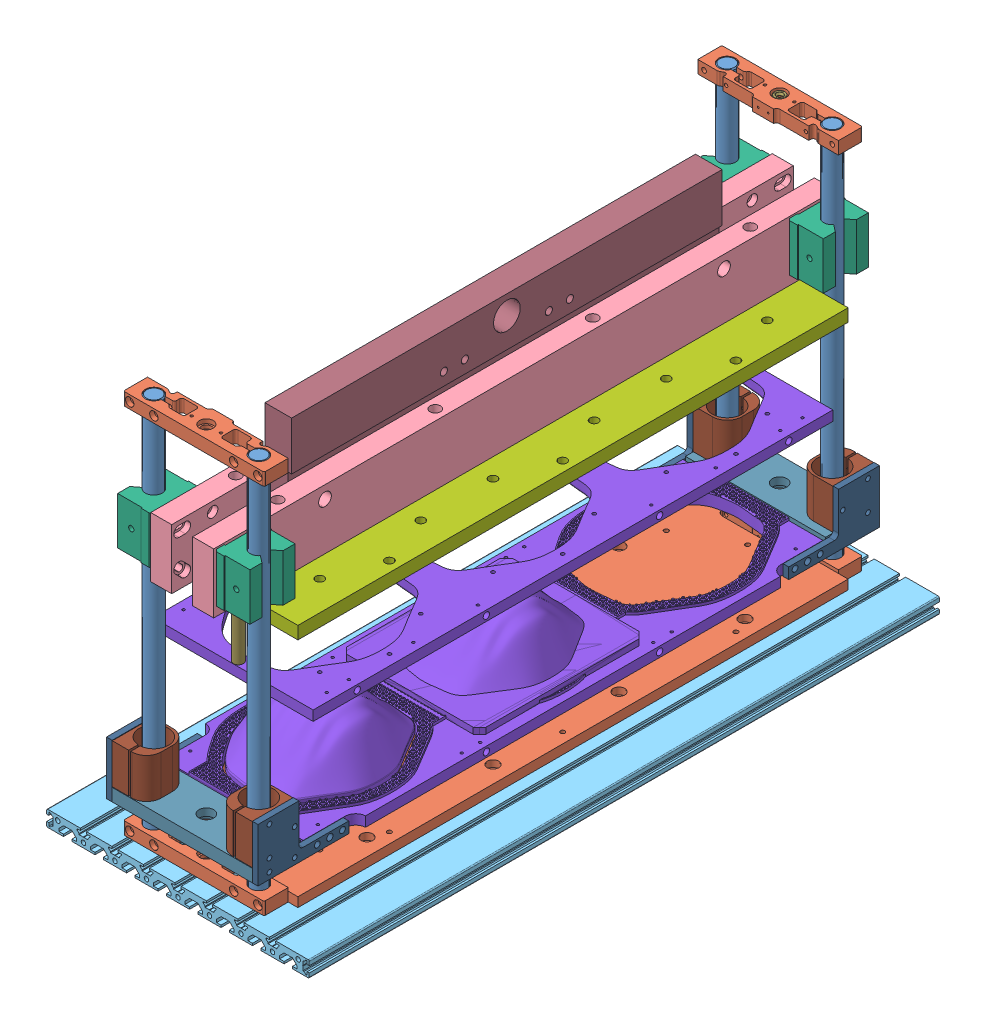
SolidWorks assembly MaskPress, configuration Default. Lengths in mm.
Overall size (250 384.22 600.9).
40 component instances, 14 part files, 64 mates.
Components (placement in the parent):
- 7121045-Z-ZShaft-2: 7121045-Z-ZShaft [Default] at (50 198 -273) x (0.850802 0 -0.525486) z (0.525486 0 0.850802) size (16 366 16)
- 7121045-Z-ZShaft-3: 7121045-Z-ZShaft [Default] at (-50 198 -273) x (0.889687 0 -0.456571) z (0.456571 0 0.889687) size (16 366 16)
- 2MaskBottomPlate2-1: 2MaskBottomPlate2 [Default] at (0 21 -273) x (1 0 0) z (0 0 -1) size (134 12 27.75)
- 2MaskBottomPlate2-2: 2MaskBottomPlate2 [Default] at (0 375 -273) x (1 0 0) z (0 0 -1) size (134 12 27.75)
- 7121502-6mmBearing-2: 7121502-6mmBearing [Default] at (0 378.5 -273) x (0.973392 0 -0.229147) z (0 -1 0) size (10 10 3)
- 7121045-Z-ZShaft-4: 7121045-Z-ZShaft [Default] at (50 198 273) x (0.850802 0 0.525486) z (-0.525486 0 0.850802) size (16 366 16)
- 7121045-Z-ZShaft-5: 7121045-Z-ZShaft [Default] at (-50 198 273) x (0.889687 0 0.456571) z (-0.456571 0 0.889687) size (16 366 16)
- 2MaskBottomPlate2-3: 2MaskBottomPlate2 [Default] at (0 21 273) x (-1 0 0) z (0 0 1) size (134 12 27.75)
- 2MaskBottomPlate2-4: 2MaskBottomPlate2 [Default] at (0 375 273) x (-1 0 0) z (0 0 1) size (134 12 27.75)
- Crosspiece-1: Crosspiece [Default] at (20 232.7807 0) x (1 0 0) z (0 0 -1) size (20 57 592)
- HFSQN4-15250-600-1: HFSQN4-15250-600 [Default] at (0 15 -300) x (-1 0 0) z (0 0 1) size (250 15 600)
- BearingBlock-RLG16-1: BearingBlock-RLG16 [BearingBlock] at (50 280.7807 -273) x (0 0 -1) z (0 1 0) size (50.4 50.24 45)
- BearingBlock-RLG16-2: BearingBlock-RLG16 [BearingBlock] at (50 280.7807 273) x (0 0 -1) z (0 1 0) size (50.4 50.24 45)
- Crosspiece-2: Crosspiece [Default] at (-20 232.7807 0) x (-1 0 0) z (0 0 1) size (20 57 592)
- BearingBlock-RLG16-3: BearingBlock-RLG16 [BearingBlock] at (-50 280.7807 -273) x (0 0 -1) z (0 -1 0) size (50.4 50.24 45)
- BearingBlock-RLG16-4: BearingBlock-RLG16 [BearingBlock] at (-50 280.7807 273) x (0 0 -1) z (0 -1 0) size (50.4 50.24 45)
- 2MaskBottomPlate2-5: 2MaskBottomPlate2 [Baseplate] at (0 21 273) size (161.21 9 568.5)
- TopPlate-1: TopPlate [Default] at (0 241.7807 0) x (0 0 -1) z (1 0 0) size (524 75.7 152.4)
- N95_Mask_Mold-1: N95_Mask_Mold [Default] at (-3.8223 61.75 0) x (0 0 -1) z (0 1 0) size (147.26 125.94 76.23)
- ShoulderScrew-ISO7379-1: ShoulderScrew-ISO7379 [M5-6Dx20L] at (28.2071 44.02 -71.5893) x (0 -1 0) z (0 0 1) size (31.12 11.61 10)
- N95_Mask_Mold-2: N95_Mask_Mold [BottomDie] at (-3.8223 49.27 0) x (0 0 1) z (0 -1 0) size (495.2 152.4 81.89)
- SteelBracket-1: SteelBracket [Default] at (66.75 47.75 296) x (0 0 -1) z (1 0 0) size (86.5 50.8 5.4)
- ClampingBearingBlock-1: ClampingBearingBlock [Default] at (50 79.3 273) x (0 0 -1) z (0 1 0) size (39 32.75 38)
- ClampingBearingBlock-2: ClampingBearingBlock [Default] at (50 79.3 -273) x (0 0 1) z (0 -1 0) size (39 32.75 38)
- SteelBracket-2: SteelBracket [Default] at (72.15 47.75 -296) x (0 0 1) z (-1 0 0) size (86.5 50.8 5.4)
- SteelBracket-3: SteelBracket [Default] at (-66.75 47.75 -296) x (0 0 1) z (-1 0 0) size (86.5 50.8 5.4)
- SteelBracket-4: SteelBracket [Default] at (-72.15 47.75 296) x (0 0 -1) z (1 0 0) size (86.5 50.8 5.4)
- ClampingBearingBlock-3: ClampingBearingBlock [Default] at (-50 79.3 273) x (0 0 -1) z (0 -1 0) size (39 32.75 38)
- ClampingBearingBlock-4: ClampingBearingBlock [Default] at (-50 79.3 -273) x (0 0 1) z (0 1 0) size (39 32.75 38)
- N95_Mask_Mold-3: N95_Mask_Mold [TopDie] at (-3.8223 170.5307 0) x (0 0 -1) z (0 1 0) size (531 152.4 13.77)
- Standoff-1: Standoff [Default] at (0 235.7807 -82.5) x (0.390754 0 0.920495) z (0 -1 0) size (9.53 9.53 65)
- Standoff-2: Standoff [Default] at (0 235.7807 82.5) x (0.79002 0 -0.61308) z (0 -1 0) size (9.53 9.53 65)
- Standoff-3: Standoff [Default] at (0 235.7807 242.5) x (0.79002 0 -0.61308) z (0 -1 0) size (9.53 9.53 65)
- Standoff-4: Standoff [Default] at (0 235.7807 -242.5) x (0.390754 0 0.920495) z (0 -1 0) size (9.53 9.53 65)
- Standoff-5: Standoff [17] at (0 23 30) x (1 0 0) z (0 1 0) size (9.53 9.53 17)
- Standoff-6: Standoff [17] at (0 23 -30) x (1 0 0) z (0 1 0) size (9.53 9.53 17)
- PressConnector-1: PressConnector [Default] at (0.5 320.6807 0) x (0 0 -1) z (1 0 0) size (410 76.2 25.4)
- SpringPlate-1: SpringPlate [Default] at (0 47.75 -273) x (1 0 0) z (0 1 0) size (133.5 46 12)
- SpringPlate-2: SpringPlate [Default] at (0 47.75 273) x (-1 0 0) z (0 1 0) size (133.5 46 12)
- N95_Mask_Mold-4: N95_Mask_Mold [Default] at (-3.8223 61.75 165) x (0 0 -1) z (0 1 0) size (147.26 125.94 76.23)
Mates (geometry in assembly coordinates):
- Coincident5: coincident: plane of ? through (0 0 0) normal (1 0 0); plane of assembly through (0 0 0) normal (1 0 0)
- Concentric1: concentric: cylinder of ? through (53 -169 -249) axis (0 1 0) radius 8; cylinder of ? through (53 405.5 -249) axis (0 -1 0) radius 8
- Concentric2: concentric: cylinder of ? through (53 30.5 -279) axis (0 0 -1) radius 2.9; cylinder of ? through (53 30.5 -257) axis (0 0 -1) radius 2.1
- Concentric182: concentric aligned: cylinder of 2MaskBottomPlate2-1 through (-50 15 -273) axis (0 1 0) radius 8; cylinder of 7121045-Z-ZShaft-3 through (-50 381 -273) axis (0 1 0) radius 8
- Concentric240: concentric aligned: cylinder of 7121045-Z-ZShaft-3 through (-50 381 -273) axis (0 1 0) radius 8; cylinder of 2MaskBottomPlate2-2 through (-50 369 -273) axis (0 1 0) radius 8
- Concentric242: concentric aligned: cylinder of 7121045-Z-ZShaft-2 through (50 381 -273) axis (0 1 0) radius 8; cylinder of 2MaskBottomPlate2-2 through (50 369 -273) axis (0 1 0) radius 8
- Coincident203: coincident aligned: plane of 7121045-Z-ZShaft-2 through (55.9556 381 -276.6784) normal (0 1 0); plane of 2MaskBottomPlate2-2 through (65.5 381 -283.5) normal (0 1 0)
- Coincident204: coincident aligned: plane of 7121045-Z-ZShaft-3 through (-43.7722 381 -276.196) normal (0 1 0); plane of 2MaskBottomPlate2-2 through (65.5 381 -283.5) normal (0 1 0)
- Coincident206: coincident anti-aligned: plane of 2MaskBottomPlate2-2 through (6.5 377 -273) normal (0 1 0); plane of 7121502-6mmBearing-2 through (1.1114 377 -268.2791) normal (0 -1 0)
- Parallel2: parallel anti-aligned: plane of 2MaskBottomPlate2-2 through (65.5 369 -285) normal (0 0 -1)
- Coincident244: coincident aligned: plane of 7121045-Z-ZShaft-2 through (55.9556 15 -276.6784) normal (0 -1 0); plane of 2MaskBottomPlate2-1 through (65.5 15 -283.5) normal (0 -1 0)
- Concentric281: concentric anti-aligned: cylinder of BearingBlock-RLG16-1 through (50 303.2807 -273) axis (0 -1 0) radius 8; cylinder of 7121045-Z-ZShaft-2 through (50 381 -273) axis (0 1 0) radius 8
- Parallel4: parallel anti-aligned: plane of BearingBlock-RLG16-1 through (30 303.2807 -252.5) normal (-1 0 0)
- Concentric282: concentric anti-aligned: cylinder of BearingBlock-RLG16-2 through (50 303.2807 273) axis (0 -1 0) radius 8; cylinder of 7121045-Z-ZShaft-4 through (50 381 273) axis (0 1 0) radius 8
- Coincident254: coincident aligned: plane of BearingBlock-RLG16-1 through (50 303.2807 -273) normal (0 1 0); plane of BearingBlock-RLG16-2 through (50 303.2807 273) normal (0 1 0)
- Coincident257: coincident anti-aligned: plane of 2MaskBottomPlate2-3 through (-65.5 15 283.5) normal (0 -1 0); plane of HFSQN4-15250-600-1 through (27 15 300) normal (0 1 0)
- Coincident258: coincident aligned: unknown of HFSQN4-15250-600-1
- Coincident259: coincident anti-aligned: plane of HFSQN4-15250-600-1 through (0 15 -300) normal (-1 0 0)
- Coincident260: coincident anti-aligned: plane of HFSQN4-15250-600-1 through (-124 0 300) normal (0 -1 0)
- Concentric285: concentric aligned: cylinder of Crosspiece-1 through (37.2801 295.7807 257) axis (-1 0 0) radius 2.9; cylinder of BearingBlock-RLG16-2 through (30 295.7807 257) axis (-1 0 0) radius 2.1
- Concentric287: concentric aligned: cylinder of Crosspiece-1 through (37.2801 295.7807 -257) axis (-1 0 0) radius 2.9; cylinder of BearingBlock-RLG16-1 through (30 295.7807 -257) axis (-1 0 0) radius 2.1
- Coincident261: coincident anti-aligned: plane of Crosspiece-1 through (30 247.7807 -296) normal (1 0 0); plane of BearingBlock-RLG16-2 through (30 303.2807 252.5) normal (-1 0 0)
- Concentric288: concentric aligned: cylinder of 7121045-Z-ZShaft-4 through (50 381 273) axis (0 1 0) radius 8; cylinder of 2MaskBottomPlate2-3 through (50 15 273) axis (0 1 0) radius 8
- Coincident262: coincident anti-aligned: plane of HFSQN4-15250-600-1 through (-3 15 300) normal (0 1 0); plane of 7121004-H4A-ZShaftClamp-5 through (-35.25 15 -260) normal (0 -1 0)
- Coincident263: coincident anti-aligned: plane of HFSQN4-15250-600-1 through (0 15 -300) normal (-1 0 0); plane of 7121004-H4A-ZShaftClamp-5 through (0 21 273) normal (1 0 0)
- Coincident264: coincident anti-aligned: plane of 2MaskBottomPlate2-1 through (0 15 -262) normal (0 0 1); plane of 7121004-H4A-ZShaftClamp-5 through (-76.2 24 -262) normal (0 0 -1)
- Concentric289: concentric aligned: cylinder of Crosspiece-1 through (20 304.7807 225) axis (0 1 0) radius 2.75; cylinder of TopPlate-1 through (20 247.7807 225) axis (0 1 0) radius 2.1
- Coincident265: coincident anti-aligned: plane of Crosspiece-1 through (10 247.7807 -296) normal (0 -1 0); plane of TopPlate-1 through (0 247.7807 0) normal (0 1 0)
- Concentric290: concentric aligned: cylinder of Crosspiece-1 through (20 304.7807 -225) axis (0 1 0) radius 2.75; cylinder of TopPlate-1 through (20 247.7807 -225) axis (0 1 0) radius 2.1
- Coincident272: coincident anti-aligned: plane of assembly through (0 0 0) normal (0 0 1); plane of N95_Mask_Mold-1 through (-3.8223 61.75 0) normal (0 0 -1)
- Coincident275: coincident anti-aligned: plane of N95_Mask_Mold-1 through (0 61.75 0) normal (-1 0 0)
- Coincident276: coincident anti-aligned: plane of 2MaskBottomPlate2-5 through (-35.25 24 -260) normal (0 1 0); plane of ShoulderScrew-ISO7379-1 through (30.3416 24 -71.5893) normal (0 -1 0)
- Coincident277: coincident aligned: plane of N95_Mask_Mold-1 through (-3.8223 61.75 0) normal (-1 0 0); plane of N95_Mask_Mold-2 through (-3.8223 49.27 0) normal (-1 0 0)
- Coincident278: coincident anti-aligned: plane of N95_Mask_Mold-1 through (-3.8223 61.75 0) normal (0 0 -1); plane of N95_Mask_Mold-2 through (-3.8223 49.27 0) normal (0 0 1)
- Coincident279: coincident anti-aligned: plane of ShoulderScrew-ISO7379-1 through (32.9071 49.02 -71.5893) normal (0 1 0); plane of N95_Mask_Mold-2 through (-3.8223 49.02 165) normal (0 -1 0)
- Concentric295: concentric anti-aligned: cylinder of N95_Mask_Mold-2 through (66.75 53.75 215.5) axis (1 0 0) radius 2.1; cylinder of SteelBracket-1 through (72.15 53.75 215.5) axis (-1 0 0) radius 2.75
- Concentric297: concentric anti-aligned: cylinder of 7121045-Z-ZShaft-4 through (50 381 273) axis (0 1 0) radius 8; cylinder of ClampingBearingBlock-1 through (50 98.3 273) axis (0 -1 0) radius 14
- Parallel5: parallel aligned: plane of N95_Mask_Mold-2 through (66.75 61.03 247.5) normal (1 0 0); plane of ClampingBearingBlock-1 through (66.75 98.3 273) normal (1 0 0)
- Distance11: distance = 32 mm anti-aligned: plane of 2MaskBottomPlate2-3 through (-65.5 27 283.5) normal (0 1 0); plane of ClampingBearingBlock-1 through (50 60.3 273) normal (0 -1 0)
- Concentric298: concentric anti-aligned: cylinder of SteelBracket-1 through (72.15 79.3 261) axis (-1 0 0) radius 2.25; cylinder of ClampingBearingBlock-1 through (67 79.3 261) axis (1 0 0) radius 1.65
- Coincident288: coincident anti-aligned: plane of SteelBracket-1 through (66.75 47.75 296) normal (-1 0 0); plane of ClampingBearingBlock-1 through (66.75 98.3 273) normal (1 0 0)
- Coincident289: coincident aligned: plane of N95_Mask_Mold-2 through (-3.8223 49.27 0) normal (-1 0 0); plane of N95_Mask_Mold-3 through (-3.8223 170.5307 0) normal (-1 0 0)
- Coincident290: coincident anti-aligned: plane of N95_Mask_Mold-2 through (-3.8223 49.27 0) normal (0 0 1); plane of N95_Mask_Mold-3 through (-3.8223 170.5307 0) normal (0 0 -1)
- Concentric299: concentric anti-aligned: cylinder of N95_Mask_Mold-3 through (0 161.3207 -82.5) axis (0 -1 0) radius 1.65; cylinder of Standoff-1 through (0 170.7807 -82.5) axis (0 1 0) radius 4.7625
- Coincident291: coincident anti-aligned: plane of N95_Mask_Mold-3 through (-3.8223 170.7807 -165) normal (0 1 0); plane of Standoff-1 through (0 170.7807 -82.5) normal (0 -1 0)
- Coincident292: coincident anti-aligned: plane of TopPlate-1 through (0 235.7807 0) normal (0 -1 0); plane of Standoff-1 through (0 235.7807 -82.5) normal (0 1 0)
- Concentric300: concentric anti-aligned: cylinder of N95_Mask_Mold-3 through (0 161.3207 82.5) axis (0 -1 0) radius 1.65; cylinder of Standoff-2 through (0 170.7807 82.5) axis (0 1 0) radius 4.7625
- Coincident293: coincident anti-aligned: plane of TopPlate-1 through (0 235.7807 0) normal (0 -1 0); plane of Standoff-2 through (0 235.7807 82.5) normal (0 1 0)
- Concentric301: concentric anti-aligned: cylinder of N95_Mask_Mold-3 through (0 161.3207 242.5) axis (0 -1 0) radius 1.65; cylinder of Standoff-3 through (0 170.7807 242.5) axis (0 1 0) radius 4.7625
- Coincident294: coincident anti-aligned: plane of N95_Mask_Mold-3 through (-3.8223 170.7807 -165) normal (0 1 0); plane of Standoff-3 through (0 170.7807 242.5) normal (0 -1 0)
- Concentric302: concentric anti-aligned: cylinder of N95_Mask_Mold-3 through (0 161.3207 -242.5) axis (0 -1 0) radius 1.65; cylinder of Standoff-4 through (0 170.7807 -242.5) axis (0 1 0) radius 4.7625
- Coincident295: coincident anti-aligned: plane of N95_Mask_Mold-3 through (-3.8223 170.7807 -165) normal (0 1 0); plane of Standoff-4 through (0 170.7807 -242.5) normal (0 -1 0)
- Concentric303: concentric anti-aligned: cylinder of 2MaskBottomPlate2-5 through (0 23 -30) axis (0 1 0) radius 4.826; cylinder of Standoff-6 through (0 40 -30) axis (0 -1 0) radius 4.7625
- Concentric304: concentric anti-aligned: cylinder of 2MaskBottomPlate2-5 through (0 23 30) axis (0 1 0) radius 4.826; cylinder of Standoff-5 through (0 40 30) axis (0 -1 0) radius 4.7625
- Coincident296: coincident anti-aligned: plane of 2MaskBottomPlate2-5 through (0 23 30) normal (0 1 0); plane of Standoff-5 through (0 23 30) normal (0 -1 0)
- Coincident297: coincident anti-aligned: plane of 2MaskBottomPlate2-5 through (0 23 -30) normal (0 1 0); plane of Standoff-6 through (0 23 -30) normal (0 -1 0)
- Coincident298: coincident anti-aligned: plane of N95_Mask_Mold-1 through (0 40 -30) normal (0 -1 0); plane of Standoff-6 through (0 40 -30) normal (0 1 0)
- Concentric305: concentric anti-aligned: cylinder of Crosspiece-1 through (10 292.7807 190) axis (1 0 0) radius 6.1; cylinder of PressConnector-1 through (13.2 292.7807 190) axis (-1 0 0) radius 6.125
- Coincident299: coincident anti-aligned: plane of Crosspiece-1 through (10 247.7807 -296) normal (-1 0 0); plane of PressConnector-1 through (10 312.5807 -205) normal (1 0 0)
- Concentric306: concentric anti-aligned: cylinder of Crosspiece-1 through (10 292.7807 -190) axis (1 0 0) radius 6.1; cylinder of PressConnector-1 through (13.2 292.7807 -190) axis (-1 0 0) radius 6.125
- Concentric307: concentric anti-aligned: cylinder of 7121045-Z-ZShaft-3 through (-50 381 -273) axis (0 1 0) radius 8; cylinder of SpringPlate-1 through (-50 59.75 -273) axis (0 -1 0) radius 10
- Concentric308: concentric anti-aligned: cylinder of 7121045-Z-ZShaft-2 through (50 381 -273) axis (0 1 0) radius 8; cylinder of SpringPlate-1 through (50 59.75 -273) axis (0 -1 0) radius 10
- Coincident300: coincident aligned: plane of SteelBracket-3 through (-72.15 47.75 -296) normal (0 -1 0); plane of SpringPlate-1 through (0 47.75 -273) normal (0 -1 0)
- Coincident303: coincident aligned: plane of 2MaskBottomPlate2-1 through (0 21 -273) normal (1 0 0)
